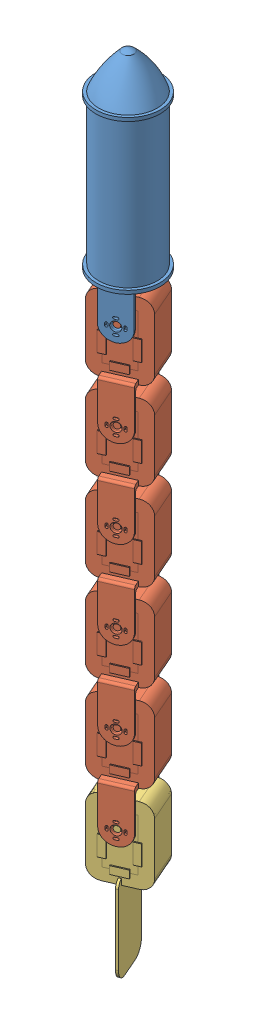
SolidWorks assembly square_tail_eel, configuration 預設. Lengths in mm.
Overall size (57.43 681.18 55.51).
7 component instances, 3 part files, 19 mates.
Components (placement in the parent):
- base_link-1: base_link [預設] at (-66.5632 -1.1579 104.9753) size (55 204.98 55)
- link2-1: link2 [預設] at (-45.8446 -161.6209 204.2877) x (0 1 0) z (0.399282 0 0.916828) size (107 45 40.5)
- link2-2: link2 [預設] at (-45.8446 -236.3209 204.2877) x (0 1 0) z (0.399282 0 0.916828) size (107 45 40.5)
- link2-3: link2 [預設] at (-45.8446 -311.0209 204.2877) x (0 1 0) z (0.399282 0 0.916828) size (107 45 40.5)
- link2-4: link2 [預設] at (-45.8446 -385.7209 204.2877) x (0 1 0) z (0.399282 0 0.916828) size (107 45 40.5)
- link2-5: link2 [預設] at (-45.8446 -460.4209 204.2877) x (0 1 0) z (0.399282 0 0.916828) size (107 45 40.5)
- short_eel_2-1: short_eel_2 [預設] at (-108.2585 -475.4636 68.9524) x (0 1 0) z (0.399282 0 0.916828) size (135 45 38)
Mates (geometry in assembly coordinates):
- 同軸心1: concentric aligned: cylinder of base_link-1 through (-52.4327 -86.9209 189.16) axis (-0.399282 0 -0.916828) radius 2.7; cylinder of link2-1 through (-51.4345 -86.9209 191.4521) axis (-0.399282 0 -0.916828) radius 2.5
- 平行1: parallel aligned: plane of base_link-1 through (-42.6286 -56.9209 181.6182) normal (0.916828 0 -0.399282); plane of link2-1 through (-19.626 -131.6209 208.1394) normal (0.916828 0 -0.399282)
- 重合/共線/共點1: coincident aligned: circle of base_link-1; plane of link2-1 through (-38.2582 -86.9209 221.7074) normal (0.399282 0 0.916828)
- 重合/共線/共點2: coincident aligned: plane of link2-1 through (-60.8832 -131.6209 226.1071) normal (-0.916828 0 0.399282); plane of link2-2 through (-60.8832 -206.3209 226.1071) normal (-0.916828 0 0.399282)
- 同軸心2: concentric anti-aligned: cylinder of link2-1 through (-53.8302 -161.6209 185.9511) axis (0.399282 0 0.916828) radius 3.7; cylinder of link2-2 through (-51.4345 -161.6209 191.4521) axis (-0.399282 0 -0.916828) radius 2.5
- 平行2: parallel aligned: plane of link2-1 through (-54.7929 -154.5209 186.3704) normal (0 -1 0); plane of link2-2 through (-54.7929 -229.2209 186.3704) normal (0 -1 0)
- 重合/共線/共點4: coincident aligned: plane of link2-1 through (-51.4345 -71.6862 191.4521) normal (-0.399282 0 -0.916828); plane of link2-2 through (-51.4345 -146.3862 191.4521) normal (-0.399282 0 -0.916828)
- 重合/共線/共點5: coincident aligned: plane of link2-2 through (-60.8832 -206.3209 226.1071) normal (-0.916828 0 0.399282); plane of link2-3 through (-60.8832 -281.0209 226.1071) normal (-0.916828 0 0.399282)
- 同軸心3: concentric anti-aligned: cylinder of link2-2 through (-53.8302 -236.3209 185.9511) axis (0.399282 0 0.916828) radius 3.7; cylinder of link2-3 through (-51.4345 -236.3209 191.4521) axis (-0.399282 0 -0.916828) radius 2.5
- 重合/共線/共點6: coincident aligned: plane of link2-2 through (-53.8302 -146.3862 185.9511) normal (-0.399282 0 -0.916828); plane of link2-3 through (-53.8302 -221.0862 185.9511) normal (-0.399282 0 -0.916828)
- 重合/共線/共點7: coincident aligned: plane of link2-3 through (-60.8832 -281.0209 226.1071) normal (-0.916828 0 0.399282); plane of link2-4 through (-60.8832 -355.7209 226.1071) normal (-0.916828 0 0.399282)
- 同軸心4: concentric anti-aligned: cylinder of link2-3 through (-53.8302 -311.0209 185.9511) axis (0.399282 0 0.916828) radius 3.7; cylinder of link2-4 through (-51.4345 -311.0209 191.4521) axis (-0.399282 0 -0.916828) radius 2.5
- 重合/共線/共點8: coincident aligned: plane of link2-3 through (-51.4345 -221.0862 191.4521) normal (-0.399282 0 -0.916828); plane of link2-4 through (-51.4345 -295.7862 191.4521) normal (-0.399282 0 -0.916828)
- 重合/共線/共點10: coincident aligned: plane of link2-4 through (-51.4345 -295.7862 191.4521) normal (-0.399282 0 -0.916828); plane of link2-5 through (-51.4345 -370.4862 191.4521) normal (-0.399282 0 -0.916828)
- 重合/共線/共點11: coincident aligned: plane of link2-4 through (-60.8832 -355.7209 226.1071) normal (-0.916828 0 0.399282); plane of link2-5 through (-60.8832 -430.4209 226.1071) normal (-0.916828 0 0.399282)
- 同軸心6: concentric anti-aligned: cylinder of link2-4 through (-53.8302 -385.7209 185.9511) axis (0.399282 0 0.916828) radius 3.7; cylinder of link2-5 through (-51.4345 -385.7209 191.4521) axis (-0.399282 0 -0.916828) radius 2.5
- 重合/共線/共點12: coincident aligned: plane of link2-5 through (-60.8832 -430.4209 226.1071) normal (-0.916828 0 0.399282); plane of short_eel_2-1 through (-60.8832 -505.1209 226.1071) normal (-0.916828 0 0.399282)
- 重合/共線/共點13: coincident aligned: plane of link2-5 through (-51.4345 -370.4862 191.4521) normal (-0.399282 0 -0.916828); plane of short_eel_2-1 through (-51.4345 -445.1862 191.4521) normal (-0.399282 0 -0.916828)
- 同軸心7: concentric anti-aligned: cylinder of link2-5 through (-53.8302 -460.4209 185.9511) axis (0.399282 0 0.916828) radius 3.7; cylinder of short_eel_2-1 through (-51.4345 -460.4209 191.4521) axis (-0.399282 0 -0.916828) radius 2.5
